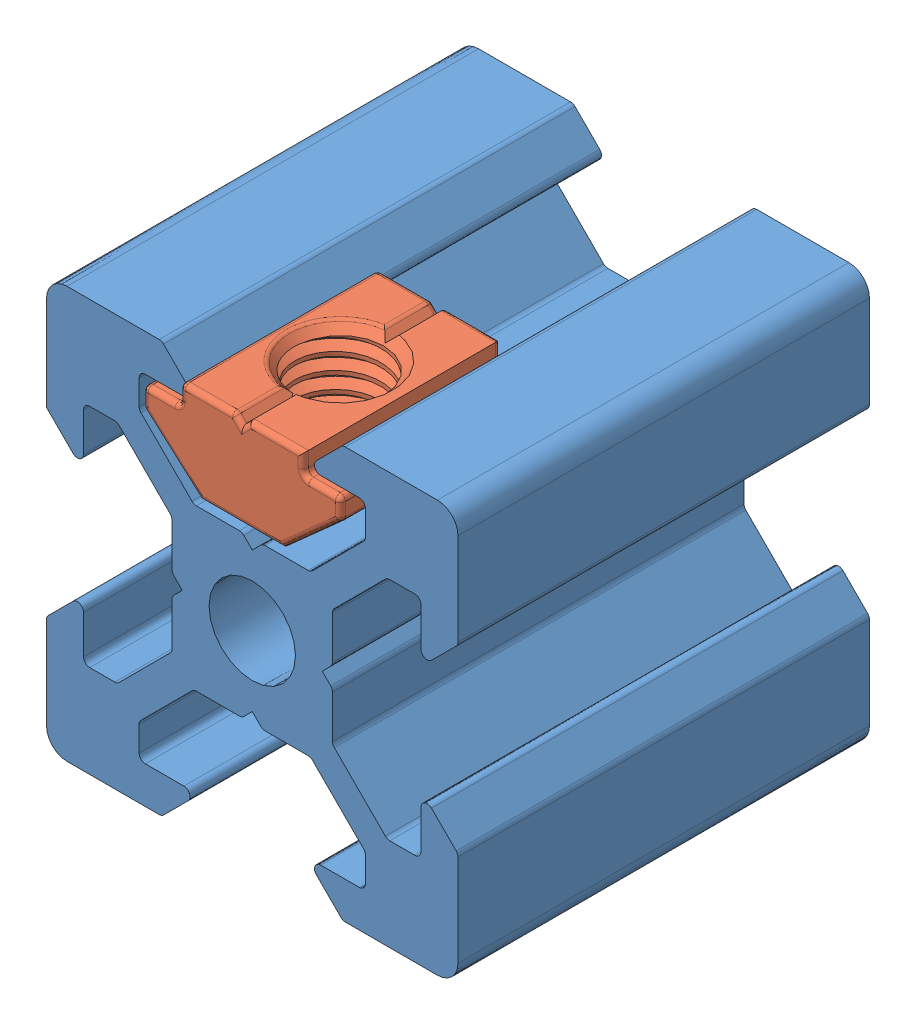
SolidWorks assembly Сборка Т-сухарь 6 паз, configuration По умолчанию. Lengths in mm.
Overall size (20 20 20.49).
2 component instances, 2 part files, 2 mates.
Components (placement in the parent):
- 2020V-1: 2020V [По умолчанию] at origin size (20 20 20)
- Т-Сухарь паз 6-1: Т-Сухарь паз 6 [По умолчанию] at (-0.0285 4.7 15.6872) size (9.6 4.59 9.6)
Mates (geometry in assembly coordinates):
- Совпадение1: coincident anti-aligned: plane of 2020V-1 through (-2.6 8.2 20) normal (0 -1 0); plane of Т-Сухарь паз 6-1 through (-4.8285 8.2 10.8872) normal (0 1 0)
- Совпадение2: coincident: cylinder of 2020V-1 through (-3.3243 8.5 20) axis (0 0 -1) radius 0.3; line of Т-Сухарь паз 6-1 through (-3.0285 8.45 11.1372) axis (0 0 1)
